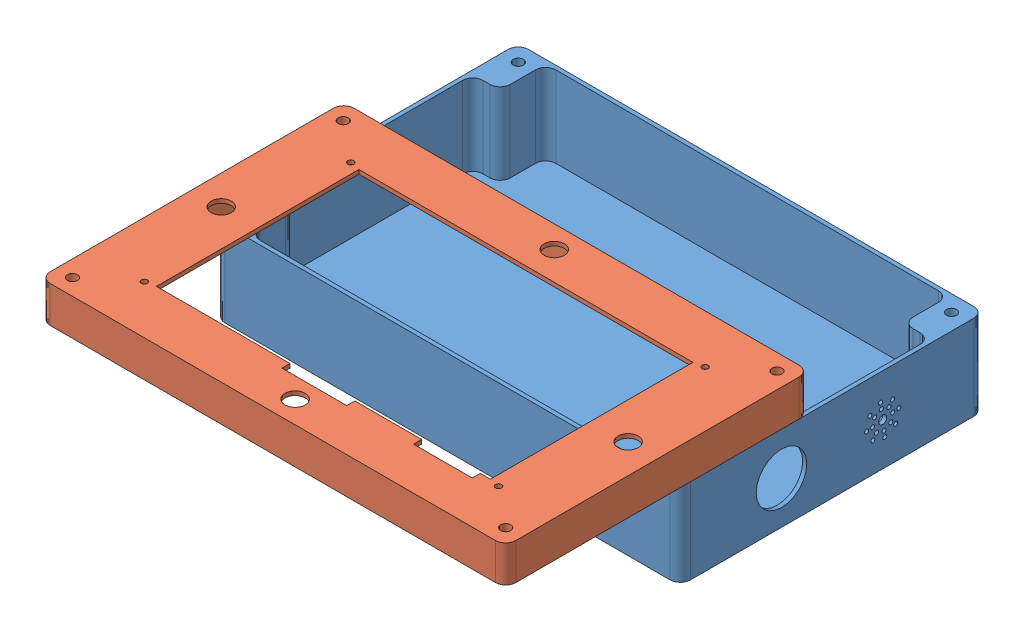
SolidWorks assembly 盒子, configuration 默认. Lengths in mm.
Overall size (230 60 236.26).
2 component instances, 2 part files, 2 mates.
Components (placement in the parent):
- 盒底-1: 盒底 [默认] at (-135.8611 -27.6605 75) size (230 42 150)
- 盒顶-1: 盒顶 [默认] at (94.1389 32.3395 161.263) x (-1 0 0) z (0 0 1) size (230 18 150)
Mates (geometry in assembly coordinates):
- 重合2: coincident aligned: line of 盒底-1 through (-135.8611 14.3395 70) axis (0 0 -1); line of 盒顶-1 through (-135.8611 14.3395 156.263) axis (0 0 -1)
- 重合4: coincident anti-aligned: line of 盒底-1 through (94.1389 14.3395 70) axis (0 0 -1); line of 盒顶-1 through (94.1389 14.3395 16.263) axis (0 0 1)
